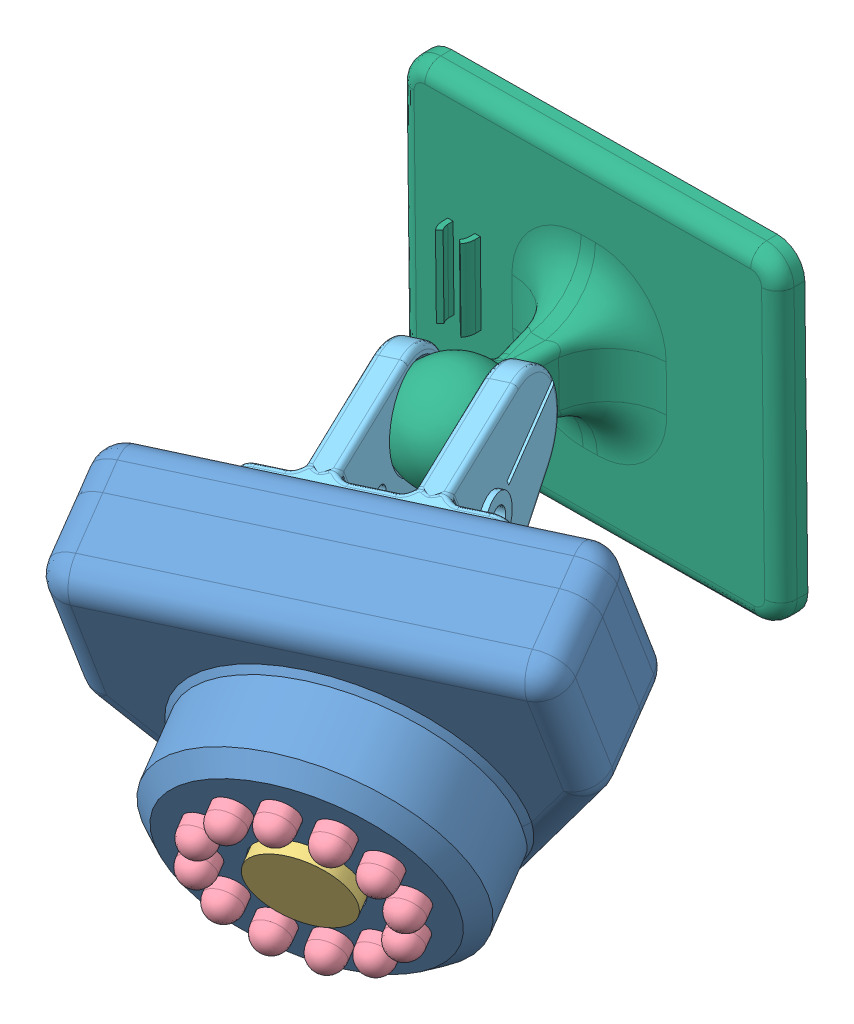
SolidWorks assembly MoCapCamera, configuration Default. Lengths in mm.
Overall size (93.72 95.64 104.6).
6 component instances, 6 part files, 13 mates.
Components (placement in the parent):
- front_shell-1: front_shell [Default] at (-2.0322 -17.9213 -12.3616) x (0.937387 0.064797 -0.342208) z (0.338527 -0.4005 0.851469) size (76 61.31 40.98)
- pcba-1: pcba [Default] at (4.3766 -9.6848 5.8765) x (0.937387 0.064797 -0.342208) z (0.338527 -0.4005 0.851469) size (64 40 1.6)
- cam-1: cam [Default] at (5.4313 -1.4792 11.1959) x (0.937387 0.064797 -0.342208) z (0.338527 -0.4005 0.851469) size (21.5 18 26.9)
- IR_led_ring-1: IR_led_ring [Default] at (12.7435 -10.13 29.5876) x (-0.916811 -0.344068 0.202669) z (-0.338527 0.4005 -0.851469) size (38.2 38.2 13)
- camera_side_mount-1: camera_side_mount [Default] at (1.2431 18.6388 3.5328) x (0.081882 0.914003 0.397359) z (-0.937387 -0.064797 0.342208) size (30.21 32 40)
- wall_side_mount-1: wall_side_mount [Default] at (-6.2045 27.4498 -15.1996) x (0.99998 0.004645 -0.004316) z (-0.004617 0.999968 0.006472) size (70 39.75 60)
Mates (geometry in assembly coordinates):
- Coincident1: coincident anti-aligned: plane of pcba-1 through (4.9183 -10.3256 7.2388) normal (0.338527 -0.4005 0.851469); plane of cam-1 through (5.4313 -1.4792 11.1959) normal (-0.338527 0.4005 -0.851469)
- Parallel1: parallel aligned: plane of pcba-1 through (20.2892 5.2704 8.4635) normal (0.937387 0.064797 -0.342208); plane of cam-1 through (14.7532 -2.5305 11.693) normal (0.937387 0.064797 -0.342208)
- Concentric1: concentric anti-aligned: cylinder of cam-1 through (12.7435 -10.13 29.5876) axis (-0.338527 0.4005 -0.851469) radius 9; cylinder of IR_led_ring-1 through (12.0664 -9.329 27.8847) axis (0.338527 -0.4005 0.851469) radius 9.1
- Concentric2: concentric aligned: cylinder of pcba-1 through (13.8678 -0.8961 8.116) axis (-0.338527 0.4005 -0.851469) radius 0.75; cylinder of cam-1 through (15.2219 -2.4981 11.5219) axis (-0.338527 0.4005 -0.851469) radius 1.75
- Concentric7: concentric aligned: cylinder of front_shell-1 through (21.8837 -20.9435 52.5773) axis (-0.338527 0.4005 -0.851469) radius 8.5; cylinder of cam-1 through (14.5377 -12.2527 34.1004) axis (-0.338527 0.4005 -0.851469) radius 8.3
- Parallel4: parallel anti-aligned: plane of front_shell-1 through (11.1802 25.0784 31.9719) normal (-0.081882 -0.914003 -0.397359); plane of pcba-1 through (8.1936 26.2345 23.1332) normal (0.081882 0.914003 0.397359)
- Coincident4: coincident anti-aligned: plane of front_shell-1 through (12.7435 -10.13 29.5876) normal (-0.338527 0.4005 -0.851469); plane of cam-1 through (12.7435 -10.13 29.5876) normal (0.338527 -0.4005 0.851469)
- Coincident5: coincident anti-aligned: plane of front_shell-1 through (12.7435 -10.13 29.5876) normal (-0.338527 0.4005 -0.851469); plane of IR_led_ring-1 through (12.7435 -10.13 29.5876) normal (0.338527 -0.4005 0.851469)
- Concentric10: concentric: sphere of camera_side_mount-1; sphere of wall_side_mount-1
- Concentric11: concentric aligned: cylinder of front_shell-1 through (18.6892 15.6057 6.9143) axis (-0.338527 0.4005 -0.851469) radius 2.3; cylinder of camera_side_mount-1 through (16.3195 18.4092 0.954) axis (-0.338527 0.4005 -0.851469) radius 1.5
- Concentric12: concentric aligned: cylinder of front_shell-1 through (-9.4324 13.6619 17.1806) axis (-0.338527 0.4005 -0.851469) radius 2.3; cylinder of camera_side_mount-1 through (-11.8021 16.4653 11.2203) axis (-0.338527 0.4005 -0.851469) radius 1.5
- Coincident6: coincident anti-aligned: plane of front_shell-1 through (-2.0322 -17.9213 -12.3616) normal (-0.338527 0.4005 -0.851469); plane of camera_side_mount-1 through (1.2431 18.6388 3.5328) normal (0.338527 -0.4005 0.851469)
- Concentric13: concentric aligned: cylinder of front_shell-1 through (34.7601 -13.1955 51.1023) axis (-0.338527 0.4005 -0.851469) radius 3.05; cylinder of IR_led_ring-1 through (27.3125 -4.3845 32.37) axis (-0.338527 0.4005 -0.851469) radius 3
